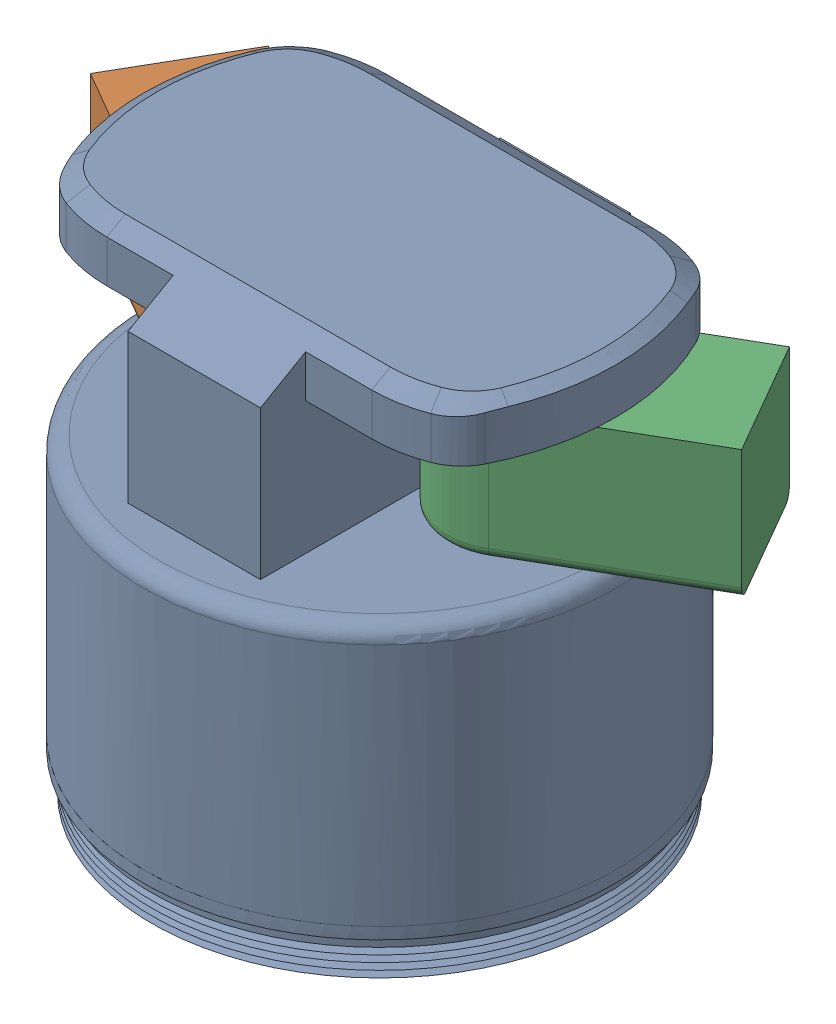
SolidWorks assembly B2580, configuration Default. Lengths in mm.
Overall size (122.92 94.5 88.91).
3 component instances, 2 part files, 6 mates.
Components (placement in the parent):
- B2581-1: B2581 [Default] at origin size (89 94.5 88.91)
- B2582-1: B2582 [Default] at (-25 3.2 0) x (-0.5 0 0.866025) z (-0.866025 0 -0.5) size (24.6 24.6 47.3)
- B2582-2: B2582 [Default] at (25 3.2 0) x (-0.5 0 -0.866025) z (0.866025 0 -0.5) size (24.6 24.6 47.3)
Mates (geometry in assembly coordinates):
- Concentric1: concentric aligned: cylinder of B2581-1 through (-25 -2.5 0) axis (0 1 0) radius 2.5; cylinder of B2582-1 through (-25 5.2 0) axis (0 1 0) radius 12.3
- Concentric2: concentric aligned: cylinder of B2581-1 through (25 -2.5 0) axis (0 1 0) radius 2.5; cylinder of B2582-2 through (25 5.2 0) axis (0 1 0) radius 12.3
- Coincident2: coincident aligned: plane of B2581-1 through (-12.3 27.8 -35) normal (0 1 0); point of B2582-2
- Coincident3: coincident aligned: plane of assembly through (-12.3 27.8 -35) normal (0 1 0)
- J12-setable: planar angle = 2.094395 rad aligned: plane of B2581-1 through (12.3 3.2 -35) normal (1 0 0); plane of B2582-2 through (49.1609 27.8 -28.1521) normal (-0.5 0 -0.866025)
- J22-notsetable: unknown = 2094.3951 mm aligned: plane of B2581-1 through (-12.3 27.8 -35) normal (-1 0 0); plane of B2582-1 through (-49.1609 3.2 -28.1521) normal (0.5 0 -0.866025)
